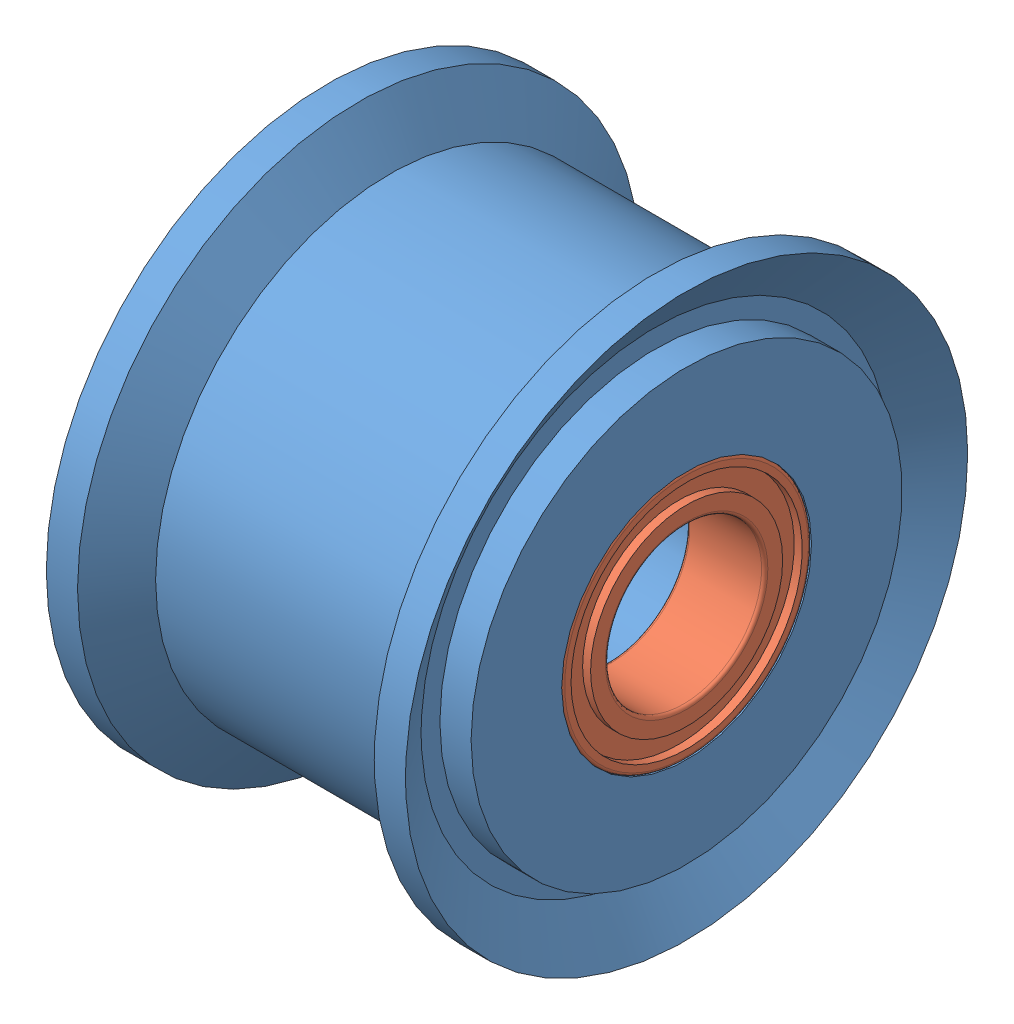
SolidWorks assembly Assem5, configuration Default. Lengths in mm.
Overall size (11.5 18 18).
3 component instances, 2 part files, 0 mates.
Components (placement in the parent):
- AFDF11_5_15_idler-1: AFDF11_5_15_idler [Default] at origin size (11.5 18 18)
- B675ZZ-1: B675ZZ [Default] at (-3.25 0 0) x (-1 0 0) z (0 0 1) size (2.5 8 8)
- B675ZZ-2: B675ZZ [Default] at (5.75 0 0) x (-1 0 0) z (0 0 1) size (2.5 8 8)
